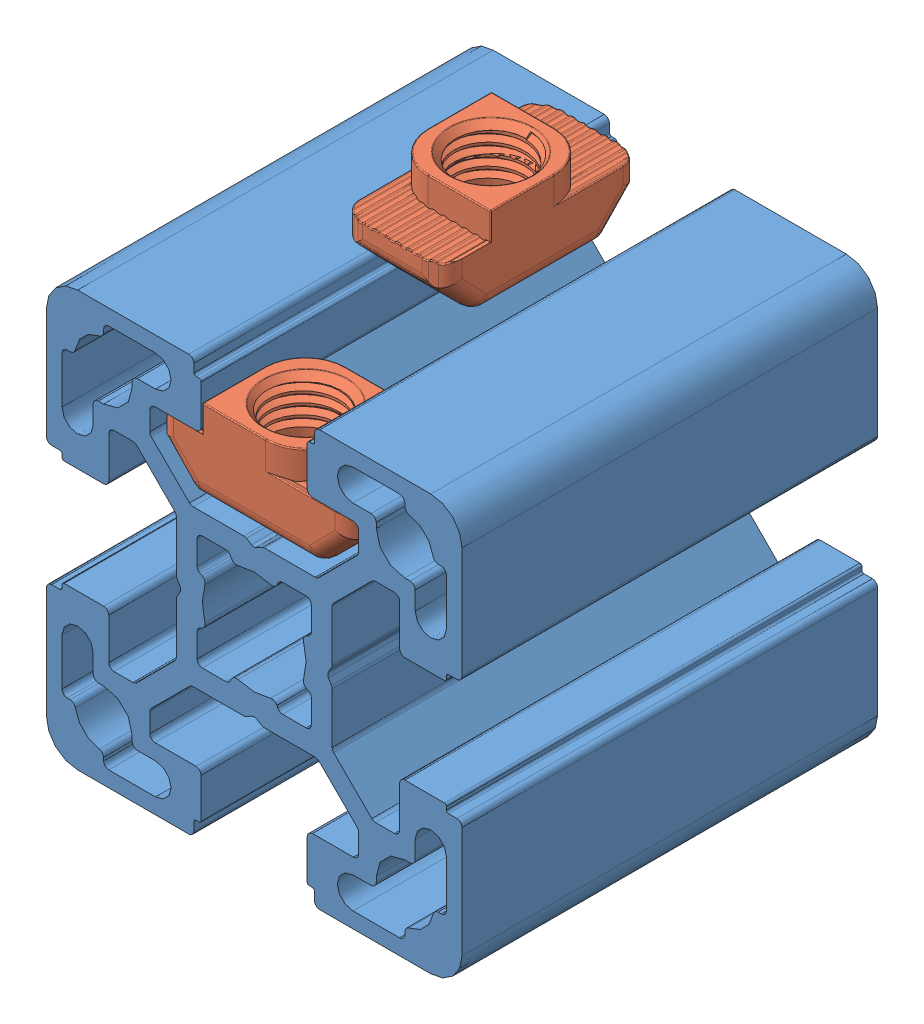
SolidWorks assembly Сборка Т-Гайка паз10, configuration По умолчанию. Lengths in mm.
Overall size (40 48.7 40.01).
3 component instances, 2 part files, 5 mates.
Components (placement in the parent):
- 40х40-1: 40х40 [По умолчанию] at origin size (40 40 40)
- Т-Гайка 10 паз-1: Т-Гайка 10 паз [По умолчанию] at (0 8.4 35.05) size (19 8.2 9.91)
- Т-Гайка 10 паз-2: Т-Гайка 10 паз [По умолчанию] at (0.05 20.5042 17.2515) x (0 0 -1) z (1 0 0) size (19 8.2 9.91)
Mates (geometry in assembly coordinates):
- Совпадение1: coincident aligned: plane of Т-Гайка 10 паз-1 through (5 14 30.1) normal (1 0 0); plane of Т-Гайка 10 паз-2 through (5 20.5042 17.2515) normal (1 0 0)
- Параллельность1: parallel anti-aligned: plane of Т-Гайка 10 паз-1 through (-5 16.6 30.1) normal (0 1 0); plane of Т-Гайка 10 паз-2 through (-4.9 20.5042 11.2515) normal (0 -1 0)
- Совпадение3: coincident aligned: plane of 40х40-1 through (0 0 40) normal (0 0 1); plane of Т-Гайка 10 паз-1 through (0 8.4 40) normal (0 0 1)
- Совпадение4: coincident anti-aligned: plane of 40х40-1 through (0 14 40) normal (0 -1 0); plane of Т-Гайка 10 паз-1 through (-9.5 14 30.1) normal (0 1 0)
- Расстояние1: distance = 0.1 mm anti-aligned: plane of 40х40-1 through (-5.1 0 40) normal (1 0 0); plane of Т-Гайка 10 паз-1 through (-5 14 30.1) normal (-1 0 0)
